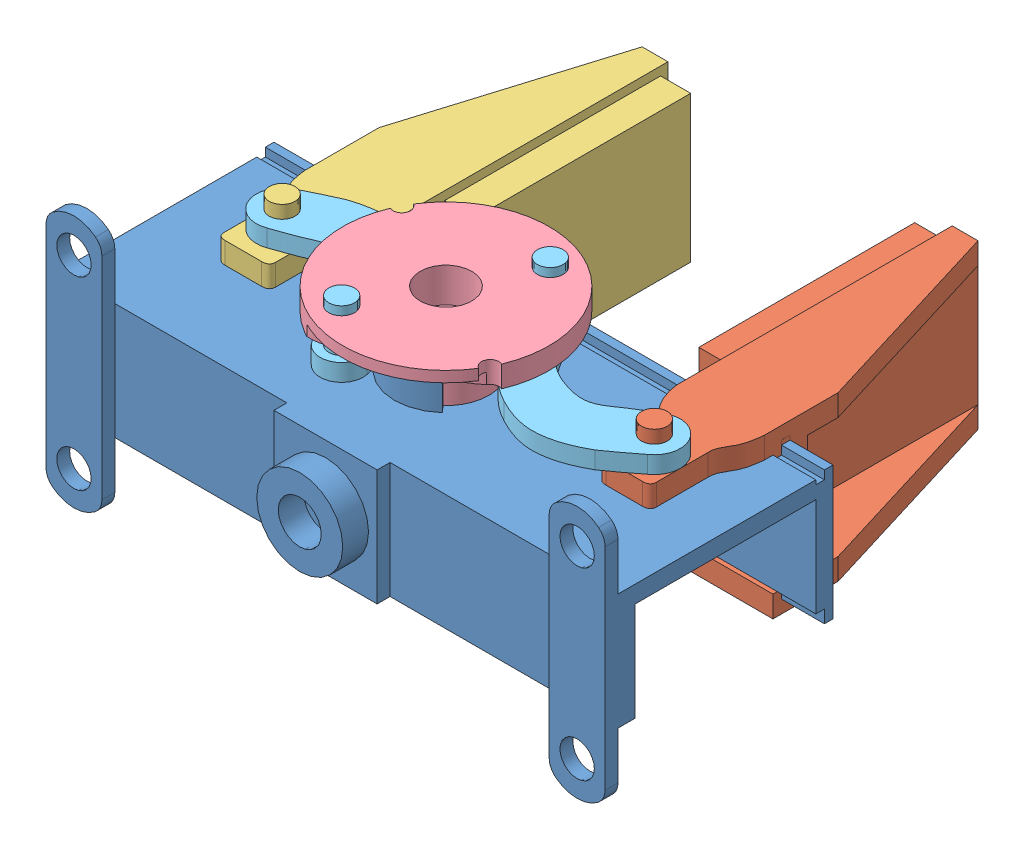
SolidWorks assembly EFECTOR FINAL FINALIZADO, configuration Predeterminado. Lengths in mm.
Overall size (65 30.96 58.5).
6 component instances, 5 part files, 12 mates.
Components (placement in the parent):
- BASE ESTATICA-1: BASE ESTATICA [Predeterminado] at (-6.7926 -4.9132 50.25) size (65 29.41 29.5)
- PINZA DERECHA-1: PINZA DERECHA [Predeterminado] at (10.562 -7.9132 51.25) size (13.67 22.5 43.74)
- PINZA IZQUIERDA-1: PINZA IZQUIERDA [Predeterminado] at (-22.4842 11.0868 51.25) x (-1 0 0) z (0 0 1) size (13.67 22.5 43.74)
- RUEDA-1: RUEDA [Predeterminado] at (-6.7926 14.5868 62.75) x (0.953046 0 -0.302825) z (0.302825 0 0.953046) size (24 8.5 24)
- EJES-1: EJES [Predeterminado] at (-28.1014 11.0868 60.4874) x (-0.862557 0 -0.505959) z (0.505959 0 -0.862557) size (25.5 7 12.5)
- EJES-2: EJES [Predeterminado] at (16.1792 11.0868 61.4874) x (0.944314 0 0.329047) z (-0.329047 0 0.944314) size (25.5 7 12.5)
Mates (geometry in assembly coordinates):
- Coincidente9: coincident anti-aligned: plane of BASE ESTATICA-1 through (-39.2926 8.5868 50.25) normal (0 0 -1); plane of PINZA DERECHA-1 through (20.7251 -5.4132 50.25) normal (0 0 1)
- Coincidente11: coincident anti-aligned: plane of BASE ESTATICA-1 through (-39.2926 8.5868 50.25) normal (0 0 -1); plane of PINZA IZQUIERDA-1 through (-45.4842 11.0868 50.25) normal (0 0 1)
- Coincidente13: coincident anti-aligned: plane of BASE ESTATICA-1 through (-6.7926 8.5868 50.25) normal (0 1 0); plane of RUEDA-1 through (-6.7926 8.5868 62.75) normal (0 -1 0)
- Concéntrica1: concentric anti-aligned: cylinder of BASE ESTATICA-1 through (-6.7926 11.5868 62.75) axis (0 -1 0) radius 5; cylinder of RUEDA-1 through (-6.7926 8.5868 62.75) axis (0 1 0) radius 5
- Coincidente14: coincident anti-aligned: plane of BASE ESTATICA-1 through (-6.7926 8.5868 50.25) normal (0 1 0); plane of PINZA IZQUIERDA-1 through (-45.4842 8.5868 51.25) normal (0 -1 0)
- Coincidente15: coincident anti-aligned: plane of BASE ESTATICA-1 through (-6.7926 8.5868 50.25) normal (0 1 0); plane of PINZA DERECHA-1 through (20.7251 8.5868 50.25) normal (0 -1 0)
- Concéntrica2: concentric anti-aligned: cylinder of PINZA DERECHA-1 through (16.1792 14.5868 61.4874) axis (0 -1 0) radius 1.5; cylinder of EJES-2 through (16.1792 10.0868 61.4874) axis (0 1 0) radius 1.5
- Coincidente16: coincident anti-aligned: plane of PINZA DERECHA-1 through (11.1992 11.0868 55.5345) normal (0 1 0); plane of EJES-2 through (16.1792 11.0868 61.4874) normal (0 -1 0)
- Concéntrica3: concentric anti-aligned: cylinder of RUEDA-1 through (-2.6546 13.0868 54.7577) axis (0 1 0) radius 1.5; cylinder of EJES-2 through (-2.6546 18.0868 54.7577) axis (0 -1 0) radius 1.5
- Concéntrica6: concentric anti-aligned: cylinder of PINZA IZQUIERDA-1 through (-28.1014 14.5868 60.4874) axis (0 -1 0) radius 1.5; cylinder of EJES-1 through (-28.1014 10.0868 60.4874) axis (0 1 0) radius 1.5
- Coincidente17: coincident anti-aligned: plane of PINZA IZQUIERDA-1 through (-23.1214 11.0868 55.5345) normal (0 1 0); plane of EJES-1 through (-28.1014 11.0868 60.4874) normal (0 -1 0)
- Concéntrica7: concentric anti-aligned: cylinder of RUEDA-1 through (-10.9306 13.0868 70.7423) axis (0 1 0) radius 1.5; cylinder of EJES-1 through (-10.9306 18.0868 70.7423) axis (0 -1 0) radius 1.5
